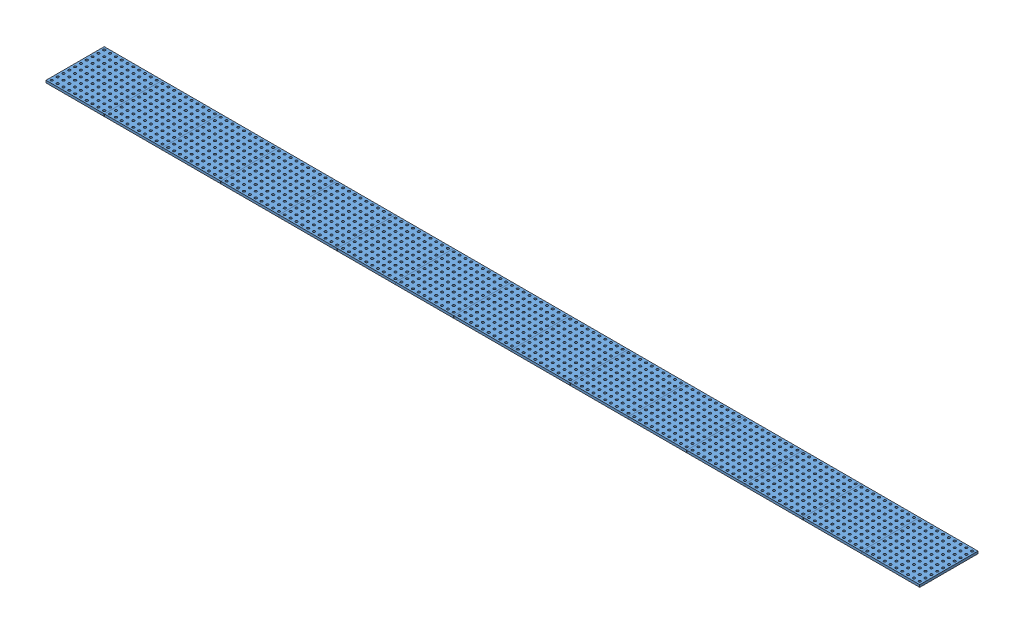
SolidWorks assembly Montagem_Base_Furada_b8, configuration Valor predeterminado. Lengths in mm.
Overall size (7500 20 500).
15 component instances, 1 part files, 0 mates.
Components (placement in the parent):
- Base_Furada_b8-1: Base_Furada_b8 [Valor predeterminado] at origin size (500 20 500)
- Base_Furada_b8-4: Base_Furada_b8 [Valor predeterminado] at (500 0 0) size (500 20 500)
- Base_Furada_b8-7: Base_Furada_b8 [Valor predeterminado] at (1000 0 0) size (500 20 500)
- Base_Furada_b8-10: Base_Furada_b8 [Valor predeterminado] at (1500 0 0) size (500 20 500)
- Base_Furada_b8-13: Base_Furada_b8 [Valor predeterminado] at (2000 0 0) size (500 20 500)
- Base_Furada_b8-14: Base_Furada_b8 [Valor predeterminado] at (2500 0 0) size (500 20 500)
- Base_Furada_b8-15: Base_Furada_b8 [Valor predeterminado] at (3000 0 0) size (500 20 500)
- Base_Furada_b8-16: Base_Furada_b8 [Valor predeterminado] at (3500 0 0) size (500 20 500)
- Base_Furada_b8-17: Base_Furada_b8 [Valor predeterminado] at (4000 0 0) size (500 20 500)
- Base_Furada_b8-18: Base_Furada_b8 [Valor predeterminado] at (4500 0 0) size (500 20 500)
- Base_Furada_b8-19: Base_Furada_b8 [Valor predeterminado] at (5000 0 0) size (500 20 500)
- Base_Furada_b8-20: Base_Furada_b8 [Valor predeterminado] at (5500 0 0) size (500 20 500)
- Base_Furada_b8-21: Base_Furada_b8 [Valor predeterminado] at (6000 0 0) size (500 20 500)
- Base_Furada_b8-22: Base_Furada_b8 [Valor predeterminado] at (6500 0 0) size (500 20 500)
- Base_Furada_b8-23: Base_Furada_b8 [Valor predeterminado] at (7000 0 0) size (500 20 500)
